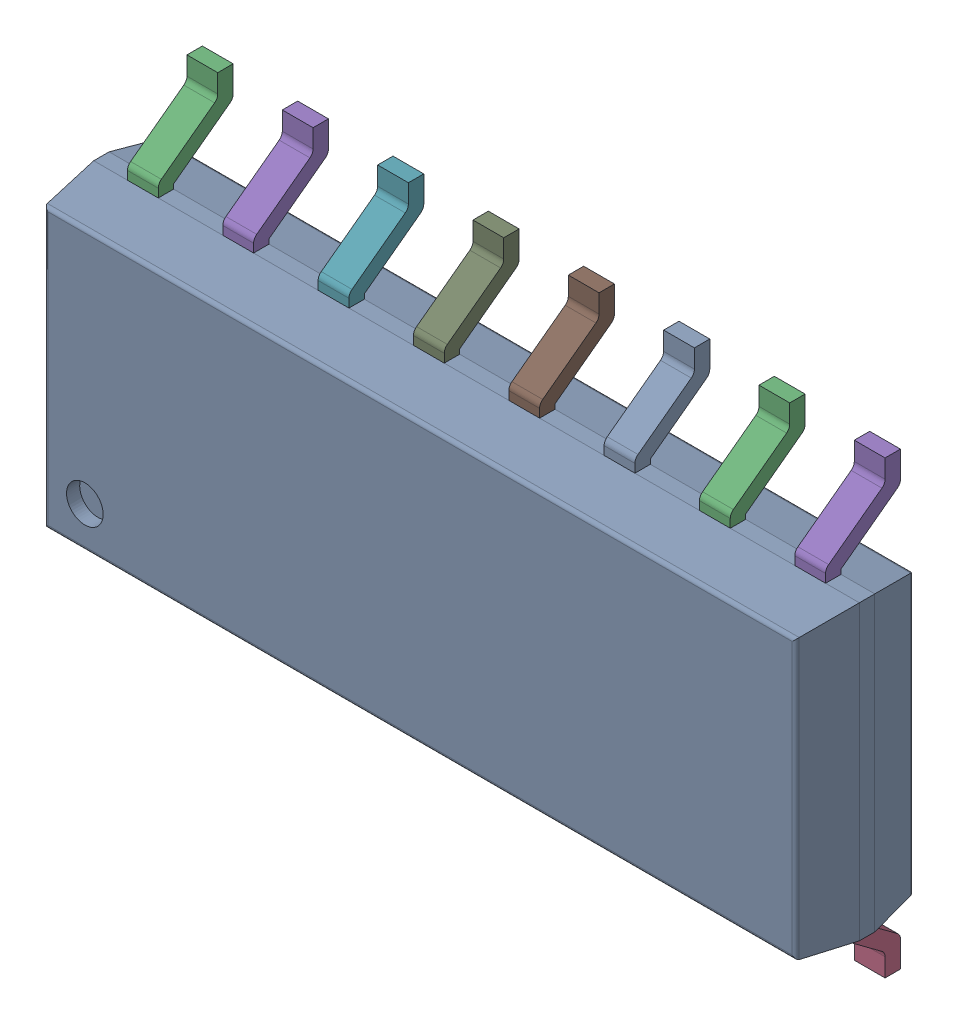
SolidWorks assembly IC15_1.step, configuration Default. Lengths in mm.
Overall size (10.2 6 1.75).
3 component instances, 2 part files, 0 mates.
Components (placement in the parent):
- 6348803008_1.step-11: 6348803008_1.step [Default] at (520.065 281.09 0) x (0 1 0) z (0 0 1) size (6 10.2 1.75)
  - Body-14_1.step-32: Body-14_1.step [Default] at origin size (3.9 10.2 1.57)
  - PinsArrayLR-15_1.step-32: PinsArrayLR-15_1.step [Default] at origin size (6 9.3 1)
